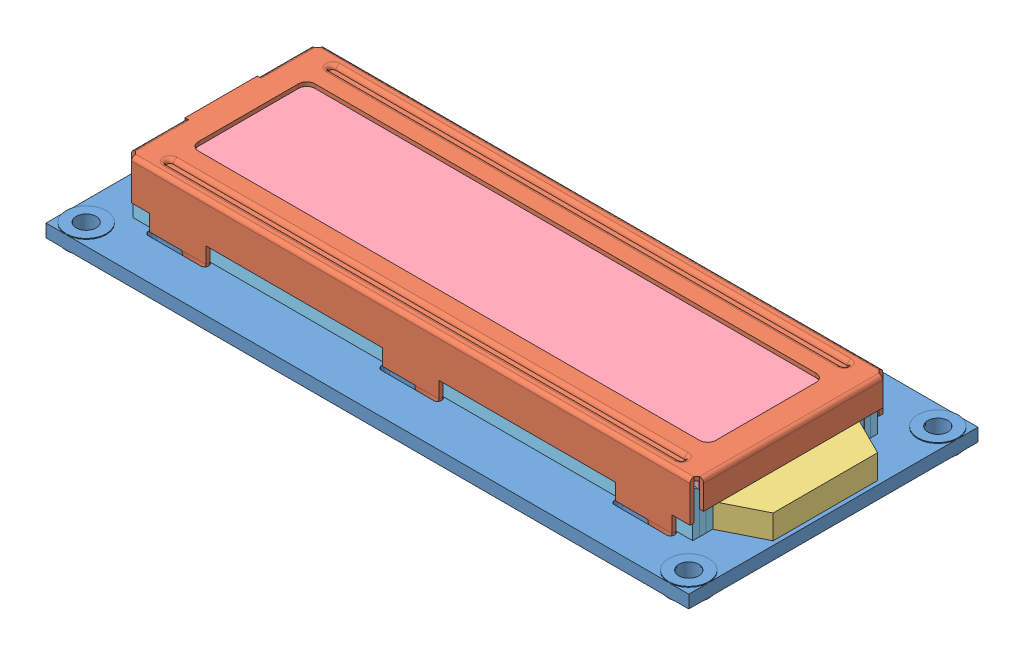
SolidWorks assembly DFRobot_1602_LCD, configuration Default. Lengths in mm.
Overall size (80 16.98 36).
7 component instances, 6 part files, 19 mates.
Components (placement in the parent):
- LCD_PCB-1: LCD_PCB [Default] at (-1.4055 -3.4444 3.0818) size (80 1.8 36)
- metal_casing-1: metal_casing [Default] at (-1.5055 3.0556 3.5818) size (71.2 10.64 25.26)
- LCDbacklight-1: LCDbacklight [Default] at (-1.7555 -3.4444 3.5818) size (74.7 3 18)
- LCD-1: LCD [Default] at (-1.6055 1.9556 3.5818) size (70.3 2.1 22)
- conductors-1: conductors [Default] at (-1.7555 -0.6944 13.8318) size (69.7 5.5 2.5)
- conductors-2: conductors [Default] at (-1.7555 -0.6944 -6.6682) size (69.7 5.5 2.5)
- conn_01x16-1: conn_01x16 [Default] at (-33.4055 -5.0444 -12.4182) x (1 0 0) z (0 -1 0) size (40.64 2.54 11.68)
Mates (geometry in assembly coordinates):
- Coincident1: coincident: plane of LCDbacklight-1 through (33.0945 -0.4444 12.5818) normal (0 0 1); plane of conductors-1 through (-1.7555 -0.6944 12.5818) normal (0 0 -1)
- Coincident2: coincident: plane of LCD_PCB-1 through (-1.4055 -3.4444 3.0818) normal (0 1 0); plane of LCDbacklight-1 through (-1.7555 -3.4444 3.5818) normal (0 -1 0)
- Coincident4: coincident: plane of LCDbacklight-1 through (33.0945 -0.4444 -5.4182) normal (0 0 -1); plane of conductors-2 through (-1.7555 -0.6944 -5.4182) normal (0 0 1)
- Coincident5: coincident: plane of LCDbacklight-1 through (33.0945 -0.4444 12.5818) normal (0 0 1); plane of conductors-1 through (-1.7555 -0.6944 12.5818) normal (0 0 -1)
- Coincident6: coincident: plane of LCD_PCB-1 through (-1.4055 -3.4444 3.0818) normal (0 1 0); plane of conductors-1 through (-36.6055 -3.4444 14.2318) normal (0 -1 0)
- Coincident7: coincident: plane of LCD_PCB-1 through (-1.4055 -3.4444 3.0818) normal (0 1 0); plane of conductors-2 through (-36.6055 -3.4444 -6.2682) normal (0 -1 0)
- Coincident8: coincident: plane of LCD_PCB-1 through (-1.4055 -3.4444 3.0818) normal (0 1 0); plane of metal_casing-1 through (-1.5055 -3.4444 3.5818) normal (0 -1 0)
- Distance3: distance = 0.1 mm: plane of metal_casing-1 through (-1.5055 3.0556 3.5818) normal (0 -1 0); plane of LCD-1 through (-1.6055 2.9556 3.5818) normal (0 1 0)
- Coincident10: coincident: plane of LCDbacklight-1 through (-36.6055 -0.4444 -5.4182) normal (-1 0 0); plane of conductors-1 through (-36.6055 2.0556 14.2318) normal (-1 0 0)
- Coincident11: coincident: plane of LCDbacklight-1 through (-36.6055 -0.4444 -5.4182) normal (-1 0 0); plane of conductors-2 through (-36.6055 2.0556 -6.2682) normal (-1 0 0)
- Coincident12: coincident: plane of LCDbacklight-1 through (-36.6055 -0.4444 -5.4182) normal (-1 0 0); plane of LCD-1 through (-36.6055 2.9556 -7.4182) normal (-1 0 0)
- Coincident13: coincident: plane of metal_casing-1 through (-36.2555 -1.4444 15.0818) normal (0 0 -1); plane of conductors-1 through (-1.7555 -0.6944 15.0818) normal (0 0 1)
- Coincident16: coincident: plane of LCDbacklight-1 through (33.0945 -0.4444 12.5818) normal (0 0 1); plane of LCD-1 through (33.3945 0.8556 12.5818) normal (0 0 1)
- Coincident18: coincident: plane of LCD_PCB-1 through (-33.6555 -5.0444 -7.9182) normal (0 0 -1); plane of metal_casing-1 through (33.2445 -1.4444 -7.9182) normal (0 0 1)
- Distance2: distance = 0.5 mm: plane of LCD_PCB-1 through (38.5945 -5.0444 -14.9182) normal (1 0 0); plane of LCDbacklight-1 through (38.0945 -3.4444 3.5818) normal (1 0 0)
- Coincident21: coincident: plane of metal_casing-1 through (-36.6055 -1.4444 -7.5682) normal (1 0 0); plane of LCD-1 through (-36.6055 2.9556 -7.4182) normal (-1 0 0)
- Concentric1: concentric: circle of LCD_PCB-1; line of conn_01x16-1 through (-33.4055 -1.1604 -12.4182) axis (0 -1 0)
- Coincident22: coincident: plane of LCD_PCB-1 through (-1.4055 -5.0444 3.0818) normal (0 -1 0); plane of conn_01x16-1 through (-33.4055 -5.0444 -12.4182) normal (0 1 0)
- Parallel1: parallel: plane of conn_01x16-1 through (-23.2455 -7.5444 -13.6882) normal (0 0 -1); plane of assembly
